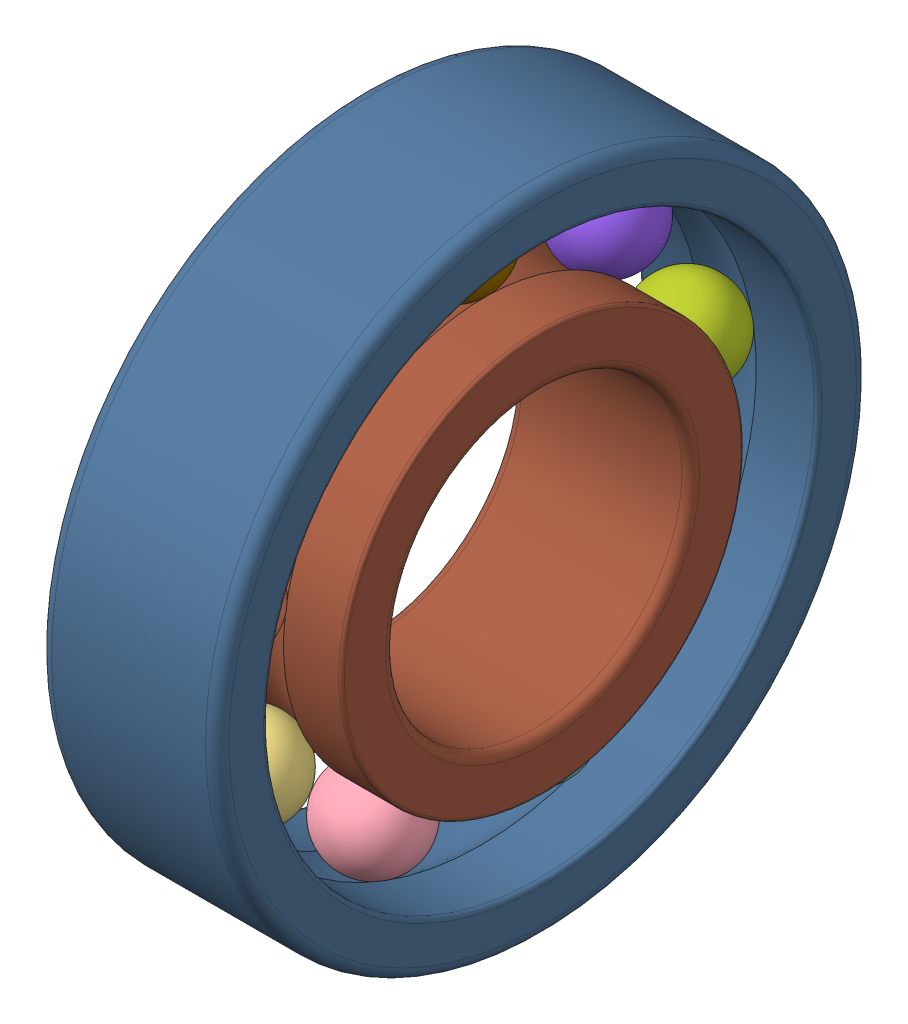
SolidWorks assembly Roulement, configuration Défaut. Lengths in mm.
Overall size (3.01 11 11).
12 component instances, 12 part files, 1 mates.
Components (placement in the parent):
- 1_PART_618_5_PART1_in_ASM_618_5-1: 1_PART_618_5_PART1_in_ASM_618_5 [Défaut] at (1.5 3.0642 2.5712) size (1.96 2.07 2.07)
- 2_PART_618_5_PART2_in_ASM_618_5-1: 2_PART_618_5_PART2_in_ASM_618_5 [Défaut] at (1.5 0.6946 3.9392) size (2.15 2.2 2.14)
- 3_PART_618_5_PART3_in_ASM_618_5-1: 3_PART_618_5_PART3_in_ASM_618_5 [Défaut] at (1.5 -2 3.4641) size (1.97 2.11 2.11)
- 4_PART_618_5_PART3_in_ASM_618_5-1: 4_PART_618_5_PART3_in_ASM_618_5 [Défaut] at (1.5 -3.7588 1.3681) size (2.08 2.02 2.1)
- 5_PART_618_5_PART3_in_ASM_618_5-1: 5_PART_618_5_PART3_in_ASM_618_5 [Défaut] at (1.5 -3.7588 -1.3681) size (1.97 2.13 2.17)
- 6_PART_618_5_PART3_in_ASM_618_5-1: 6_PART_618_5_PART3_in_ASM_618_5 [Défaut] at (1.5 -2 -3.4641) size (2.07 2.2 2.04)
- 7_PART_618_5_PART3_in_ASM_618_5-1: 7_PART_618_5_PART3_in_ASM_618_5 [Défaut] at (1.5 0.6946 -3.9392) size (2.09 2.05 2.22)
- 8_PART_618_5_PART3_in_ASM_618_5-1: 8_PART_618_5_PART3_in_ASM_618_5 [Défaut] at (1.5 3.0642 -2.5712) size (2.02 2.17 2.18)
- 9_PART_618_5_PART3_in_ASM_618_5-1: 9_PART_618_5_PART3_in_ASM_618_5 [Défaut] at (1.5 4 0) size (2.21 2.22 2.24)
- 10_PART_618_5_PART3_in_ASM_618_5-1: 10_PART_618_5_PART3_in_ASM_618_5 [Défaut] at (1.5 0 0) size (3.01 11 11)
- 11_PART_618_5_PART3_in_ASM_618_5-1: 11_PART_618_5_PART3_in_ASM_618_5 [Défaut] at (1.5 0 0) size (3.01 6.8 6.8)
- 618_5_AUTOCAD_VERSION_2004_-_2006-1: 618_5_AUTOCAD_VERSION_2004_-_2006 [Défaut] at origin
Mates (geometry in assembly coordinates):
- Coïncidente1: coincident aligned: plane of 10_PART_618_5_PART3_in_ASM_618_5-1 through (0 5.3 0) normal (-1 0 0); plane of 11_PART_618_5_PART3_in_ASM_618_5-1 through (0 3.35 0) normal (-1 0 0)
